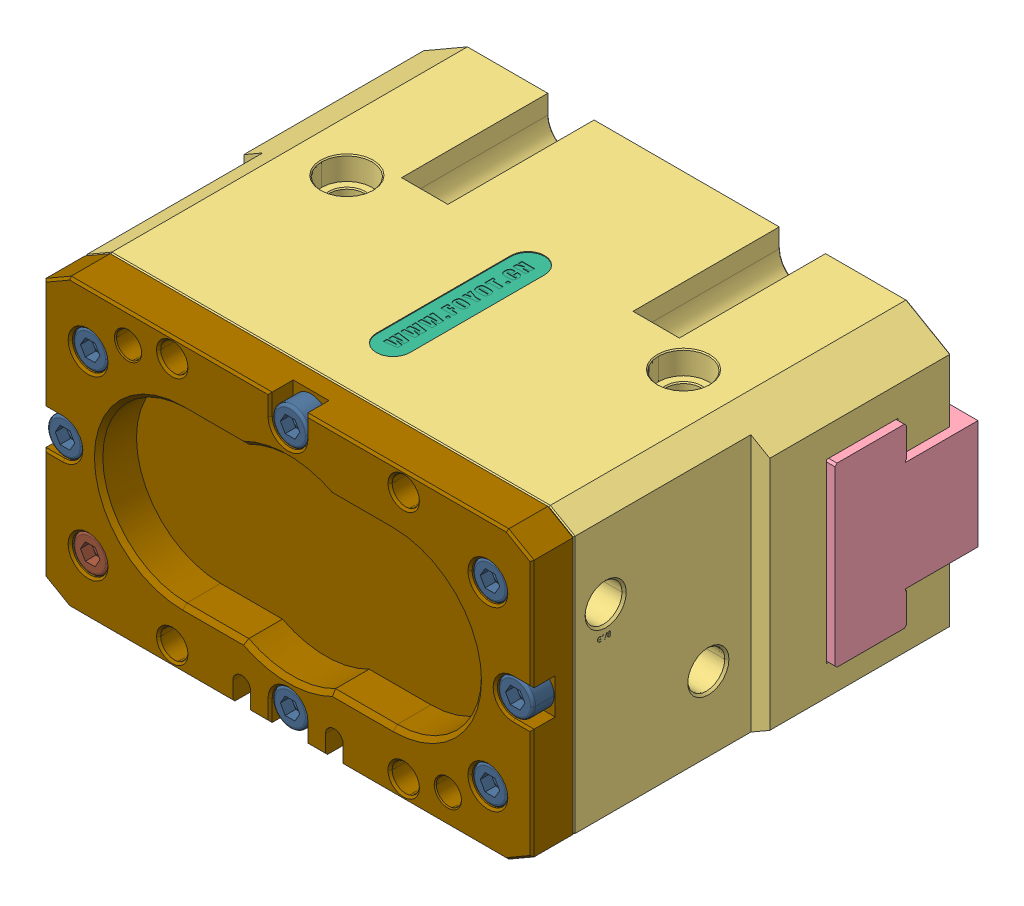
SolidWorks assembly 16771535817349, configuration 默认. Lengths in mm.
Overall size (128.96 68 100).
23 component instances, 11 part files, 0 mates.
Components (placement in the parent):
- 16771535817349.step-1: 16771535817349.step [默认] at origin size (128.96 68 100)
  - ____LOGO______.step-1: ____LOGO______.step [默认] at (-72.7703 -2.7309 164) x (0 1 0) z (-1 0 0) size (25 16 0.5)
    - FY-JGP 160-1-LOGO.step-1: FY-JGP 160-1-LOGO.step [默认] at origin size (25 16 0.5)
    - ____________-____2.step-1: ____________-____2.step [默认] at (1.423 -2.5013 0.4) size (7 7.01 0.07)
  - FY30-50E____.step-1: FY30-50E____.step [默认] at (-15.6703 -2.7309 101) size (125 68 85)
  - FY30-50E____-0.step-1: FY30-50E____-0.step [默认] at (-80.1519 -2.7309 130.5) x (0 -1 0) z (1 0 0) size (42 34.5 64)
  - FY30-50E____-0.step-2: FY30-50E____-0.step [默认] at (48.8114 -2.7309 130.5) x (0 1 0) z (-1 0 0) size (42 34.5 64)
  - LOGO__-FY30-50E.step-1: LOGO__-FY30-50E.step [默认] at (-15.6703 -2.7309 102) x (0 -1 0) z (0 0 -1) size (40 24 1)
  - ____7.step-1: ____7.step [默认] at (-15.6703 30.0691 155) x (0 0 -1) z (0 1 0) size (40 8 1)
  - ____FY30-50E.step-1: ____FY30-50E.step [默认] at (-15.6703 -35.5309 155) x (0 0 1) z (0 -1 0) size (40 8 1)
  - hexagon socket button head screws gb_GB_SOCKET_TYPE7 M3X6-N.step-1: hexagon socket button head screws gb_GB_SOCKET_TYPE7 M3X6-N.step [默认] at (-24.6703 -19.7309 99.35) x (0 0 1) z (-1 0 0) size (7.65 5.7 5.7)
  - hexagon socket button head screws gb_GB_SOCKET_TYPE7 M3X6-N.step-2: hexagon socket button head screws gb_GB_SOCKET_TYPE7 M3X6-N.step [默认] at (-24.6703 14.2691 99.35) x (0 0 1) z (-1 0 0) size (7.65 5.7 5.7)
  - hexagon socket button head screws gb_GB_SOCKET_TYPE7 M3X6-N.step-3: hexagon socket button head screws gb_GB_SOCKET_TYPE7 M3X6-N.step [默认] at (-6.6703 14.2691 99.35) x (0 0 1) z (-1 0 0) size (7.65 5.7 5.7)
  - hexagon socket button head screws gb_GB_SOCKET_TYPE7 M3X6-N.step-4: hexagon socket button head screws gb_GB_SOCKET_TYPE7 M3X6-N.step [默认] at (-6.6703 -19.7309 99.35) x (0 0 1) z (-1 0 0) size (7.65 5.7 5.7)
  - FY30-50E____-1.step-1: FY30-50E____-1.step [默认] at (-15.6703 -2.7309 186) size (116 68 10)
  - hexagon socket head cap screws gb_GB_FASTENER_SCREWS_HSHCS M5X16-N.step-1: hexagon socket head cap screws gb_GB_FASTENER_SCREWS_HSHCS M5X16-N.step [默认] at (31.8297 18.2691 195.5) x (0 0 -1) z (1 0 0) size (21 8.5 8.5)
  - hexagon socket head cap screws gb_GB_FASTENER_SCREWS_HSHCS M5X16-N.step-2: hexagon socket head cap screws gb_GB_FASTENER_SCREWS_HSHCS M5X16-N.step [默认] at (37.8297 -2.7309 195.5) x (0 0 -1) z (1 0 0) size (21 8.5 8.5)
  - hexagon socket head cap screws gb_GB_FASTENER_SCREWS_HSHCS M5X16-N.step-3: hexagon socket head cap screws gb_GB_FASTENER_SCREWS_HSHCS M5X16-N.step [默认] at (31.8297 -23.7309 195.5) x (0 0 -1) z (1 0 0) size (21 8.5 8.5)
  - hexagon socket head cap screws gb_GB_FASTENER_SCREWS_HSHCS M5X16-N.step-4: hexagon socket head cap screws gb_GB_FASTENER_SCREWS_HSHCS M5X16-N.step [默认] at (-15.6703 -31.7309 195.5) x (0 0 -1) z (1 0 0) size (21 8.5 8.5)
  - hexagon socket head cap screws gb_GB_FASTENER_SCREWS_HSHCS M5X20-N.step-1: hexagon socket head cap screws gb_GB_FASTENER_SCREWS_HSHCS M5X20-N.step [默认] at (-63.1703 -23.7309 195.5) x (0 0 -1) z (1 0 0) size (25 8.5 8.5)
  - hexagon socket head cap screws gb_GB_FASTENER_SCREWS_HSHCS M5X16-N.step-5: hexagon socket head cap screws gb_GB_FASTENER_SCREWS_HSHCS M5X16-N.step [默认] at (-69.1703 -2.7309 195.5) x (0 0 -1) z (1 0 0) size (21 8.5 8.5)
  - hexagon socket head cap screws gb_GB_FASTENER_SCREWS_HSHCS M5X16-N.step-6: hexagon socket head cap screws gb_GB_FASTENER_SCREWS_HSHCS M5X16-N.step [默认] at (-63.1703 18.2691 195.5) x (0 0 -1) z (1 0 0) size (21 8.5 8.5)
  - hexagon socket head cap screws gb_GB_FASTENER_SCREWS_HSHCS M5X16-N.step-7: hexagon socket head cap screws gb_GB_FASTENER_SCREWS_HSHCS M5X16-N.step [默认] at (-15.6703 26.2691 195.5) x (0 0 -1) z (1 0 0) size (21 8.5 8.5)
